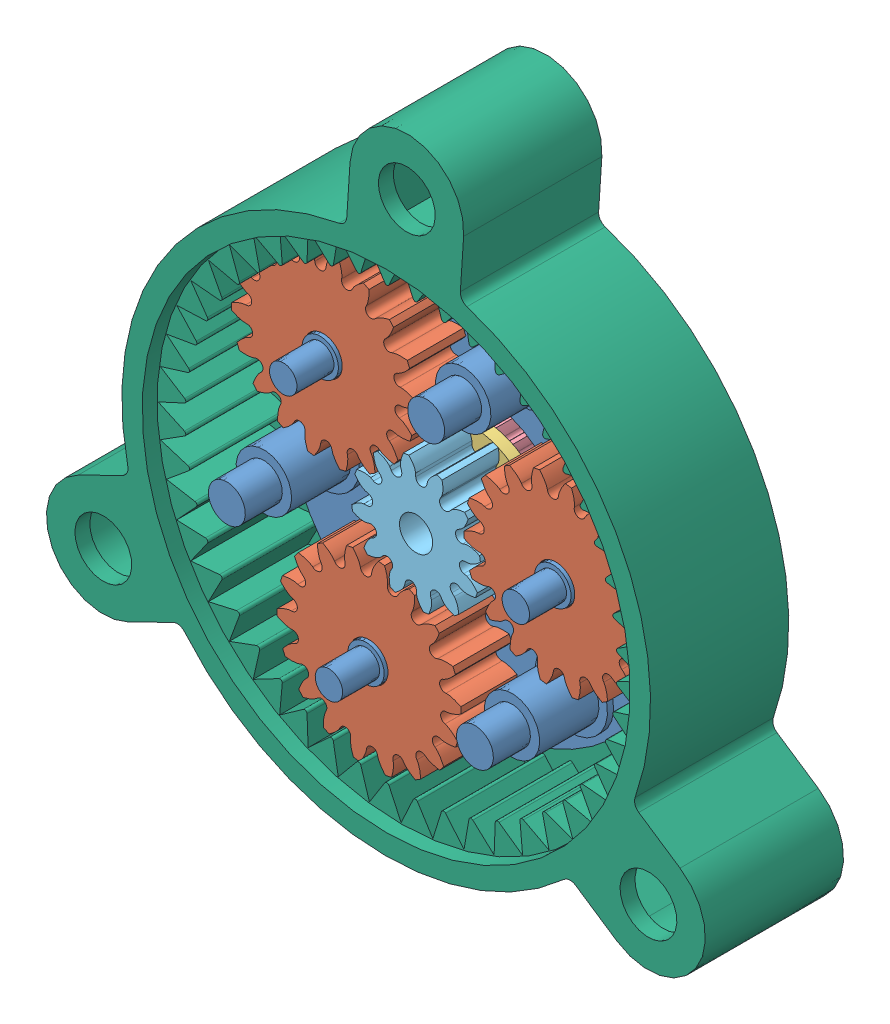
SolidWorks assembly OrangeStack, configuration Default. Lengths in mm.
Overall size (37.51 36.34 9.79).
10 component instances, 7 part files, 24 mates.
Components (placement in the parent):
- OrangeArmDisk-1: OrangeArmDisk [Default] at (-2.3713 17.6744 15.0981) x (-0.758293 -0.651914 0) z (0 0 1) size (20.9 20.9 7.39)
- OrangePlanetGear-1: OrangePlanetGear [Default] at (5.1165 19.0874 16.6221) x (0.613484 0.789708 0) z (0 0 1) size (9.76 9.86 3.01)
- OrangePlanetGear-2: OrangePlanetGear [Default] at (-4.8916 10.4833 16.6221) x (-0.377677 0.925938 0) z (0 0 1) size (9.76 9.86 3.01)
- OrangePlanetGear-3: OrangePlanetGear [Default] at (-7.3389 23.4526 16.6221) x (0.377677 -0.925938 0) z (0 0 1) size (9.76 9.86 3.01)
- OrangeSunGear-1: OrangeSunGear [Default] at (-2.3713 17.6744 12.9899) x (-0.779281 -0.626675 0) z (0 0 1) size (9.6 9.6 6.64)
  - OrangeIntermediaryPlate-1: OrangeIntermediaryPlate [Default] at (0 0 3.0099) x (0.83755 -0.546361 0) z (0 0 1) size (6.93 6.93 0.62)
  - OrangeSpurSmall-2: OrangeSpurSmall [Default] at origin size (5.78 5.84 3.01)
  - OrangeSpurLarge-2: OrangeSpurLarge [Default] at (0 0 3.6322) size (6.93 6.93 3.01)
- OrangeDriveDisk-1: OrangeDriveDisk [Default] at (-2.3713 17.6744 21.2957) x (0.758293 0.651914 0) z (0 0 -1) size (20.43 20.9 2.98) (hidden)
- HousingCase-1: HousingCase [Default] at (-2.3713 17.6744 21.2322) x (0.997859 -0.065403 0) z (0 0 1) size (35.35 34.1 7.98)
Mates (geometry in assembly coordinates):
- Concentric1: concentric aligned: cylinder of OrangeArmDisk-1 through (5.1165 19.0874 19.7971) axis (0 0 -1) radius 0.9779; cylinder of OrangePlanetGear-1 through (5.1165 19.0874 19.632) axis (0 0 -1) radius 1.016
- Concentric2: concentric aligned: cylinder of OrangeArmDisk-1 through (-4.8916 10.4833 19.7971) axis (0 0 -1) radius 0.9779; cylinder of OrangePlanetGear-2 through (-4.8916 10.4833 19.632) axis (0 0 -1) radius 1.016
- Concentric3: concentric aligned: cylinder of OrangeArmDisk-1 through (-7.3389 23.4526 19.7971) axis (0 0 -1) radius 0.9779; cylinder of OrangePlanetGear-3 through (-7.3389 23.4526 19.632) axis (0 0 -1) radius 1.016
- Coincident1: coincident anti-aligned: plane of OrangeArmDisk-1 through (-4.8916 10.4833 16.6221) normal (0 0 1); plane of OrangePlanetGear-2 through (-4.8916 10.4833 16.6221) normal (0 0 -1)
- Coincident2: coincident anti-aligned: plane of OrangeArmDisk-1 through (-7.3389 23.4526 16.6221) normal (0 0 1); plane of OrangePlanetGear-3 through (-7.3389 23.4526 16.6221) normal (0 0 -1)
- Coincident3: coincident anti-aligned: plane of OrangeArmDisk-1 through (5.1165 19.0874 16.6221) normal (0 0 1); plane of OrangePlanetGear-1 through (5.1165 19.0874 16.6221) normal (0 0 -1)
- Coincident4: coincident anti-aligned: plane of OrangeArmDisk-1 through (-2.3713 17.6744 15.0981) normal (0 0 -1); plane of HousingCase-1 through (-1.7234 27.5592 15.0981) normal (0 0 1)
- Concentric4: concentric aligned: cylinder of OrangeArmDisk-1 through (-2.3713 17.6744 16.2919) axis (0 0 -1) radius 4.9276; cylinder of HousingCase-1 through (-2.3713 17.6744 21.2322) axis (0 0 -1) radius 9.906
- Concentric8: concentric aligned: cylinder of OrangeArmDisk-1 through (-2.3713 17.6744 16.2919) axis (0 0 -1) radius 4.9276; cylinder of OrangeSunGear-1/OrangeSpurSmall-2 through (-2.3713 17.6744 15.9998) axis (0 0 -1) radius 0.889
- Coincident11: coincident aligned: plane of OrangePlanetGear-1 through (5.1165 19.0874 19.632) normal (0 0 1); plane of OrangeSunGear-1/OrangeSpurLarge-2 through (-2.3713 17.6744 19.632) normal (0 0 1)
- Parallel2: parallel: plane of OrangePlanetGear-3; plane of assembly through (0 0 0) normal (0 1 0)
- Parallel3: parallel: plane of OrangePlanetGear-2; plane of assembly through (0 0 0) normal (0 1 0)
- Parallel4: parallel: plane of OrangePlanetGear-1; plane of assembly through (0 0 0) normal (0 1 0)
- Angle1: planar angle = 0.261799 rad: plane of OrangeSunGear-1; plane of assembly through (0 0 0) normal (0 1 0)
- GearMate6: gear = 1219.2 : 457.2 mm: cylinder of OrangePlanetGear-1 through (5.1165 19.0874 19.632) axis (0 0 -1) radius 1.016; cylinder of HousingCase-1 through (-2.3713 17.6744 21.2322) axis (0 0 -1) radius 9.906
- GearMate7: gear = 1219.2 : 457.2 mm: cylinder of OrangePlanetGear-2 through (-4.8916 10.4833 19.632) axis (0 0 -1) radius 1.016; cylinder of HousingCase-1 through (-2.3713 17.6744 21.2322) axis (0 0 -1) radius 9.906
- GearMate8: gear = 1219.2 : 457.2 mm: cylinder of OrangePlanetGear-3 through (-7.3389 23.4526 19.632) axis (0 0 -1) radius 1.016; cylinder of HousingCase-1 through (-2.3713 17.6744 21.2322) axis (0 0 -1) radius 9.906
- GearMate9: gear = 304.8 : 457.2 mm: cylinder of OrangePlanetGear-1 through (5.1165 19.0874 19.632) axis (0 0 -1) radius 1.016; cylinder of OrangeSunGear-1/OrangeSpurLarge-2 through (-2.3713 17.6744 19.632) axis (0 0 -1) radius 0.889
- GearMate10: gear = 457.2 : 304.8 mm: cylinder of OrangePlanetGear-3 through (-2.3713 10.0544 19.632) axis (0 0 -1) radius 1.016; cylinder of OrangeSunGear-1/OrangeSpurLarge-2 through (-2.3713 17.6744 19.632) axis (0 0 -1) radius 0.889
- GearMate11: gear = 457.2 : 304.8 mm: cylinder of OrangeSunGear-1/OrangeSpurLarge-2 through (-2.3713 17.6744 19.632) axis (0 0 -1) radius 0.889; cylinder of OrangePlanetGear-2 through (4.2278 21.4844 19.632) axis (0 0 -1) radius 1.016
- Concentric11: concentric aligned: cylinder of OrangeArmDisk-1 through (2.9274 11.511 21.7783) axis (0 0 -1) radius 0.9906; cylinder of OrangeDriveDisk-1 through (2.9274 11.511 21.2957) axis (0 0 -1) radius 0.9906
- Coincident12: coincident anti-aligned: plane of OrangeArmDisk-1 through (2.9274 11.511 19.7971) normal (0 0 1); plane of OrangeDriveDisk-1 through (2.9274 11.511 19.7971) normal (0 0 -1)
- Concentric12: concentric aligned: cylinder of OrangeArmDisk-1 through (5.1165 19.0874 21.7783) axis (0 0 -1) radius 0.7366; cylinder of OrangeDriveDisk-1 through (5.1165 19.0874 21.2957) axis (0 0 -1) radius 0.7366
- Parallel13: parallel aligned: plane of OrangeArmDisk-1 through (-2.3713 17.6744 15.0981) normal (0 1 0); plane of assembly through (0 0 0) normal (0 1 0)
